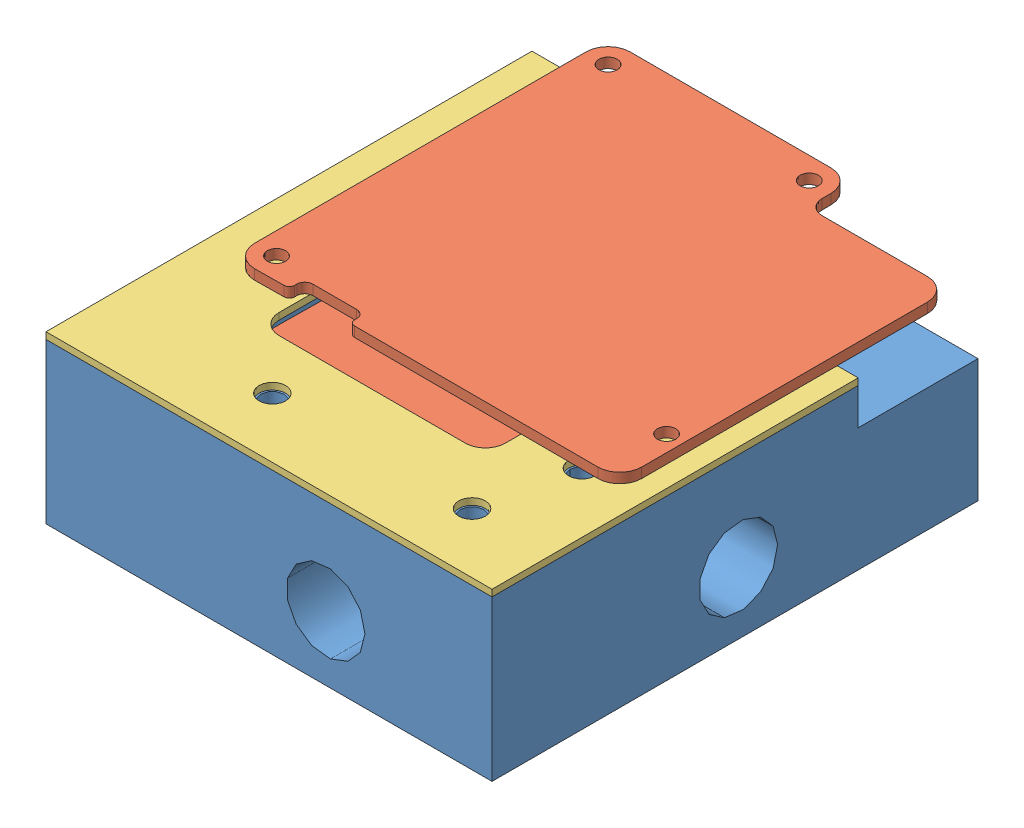
SolidWorks assembly SCK2.0Assembly, configuration Default. Lengths in mm.
Overall size (73.34 36 73).
3 component instances, 3 part files, 7 mates.
Components (placement in the parent):
- BaseSCK2.0-1: BaseSCK2.0 [Default] at origin size (67 24 73)
- SCK2.0MiCS-1: SCK2.0MiCS [Default] at (73.878 20.007 -12.5536) x (-1 0 0) z (0 0 -1) size (58.4 15.1 56.64)
- SCKClip-2: SCKClip [Default] at (52 20.5 -15) size (67 1 73)
Mates (geometry in assembly coordinates):
- Parallel1: parallel anti-aligned: plane of BaseSCK2.0-1 through (0 15 0) normal (0 1 0); plane of SCK2.0MiCS-1 through (15.1618 18.5 -23.4268) normal (0 -1 0)
- Parallel2: parallel aligned: plane of BaseSCK2.0-1 through (0 15 0) normal (-1 0 0); plane of SCK2.0MiCS-1 through (40.5073 17.4 -32.8429) normal (-1 0 0)
- Coincident1: coincident anti-aligned: plane of BaseSCK2.0-1 through (0 18.5 0) normal (0 1 0); plane of SCK2.0MiCS-1 through (15.1618 18.5 -23.4268) normal (0 -1 0)
- Concentric1: concentric aligned: circle of BaseSCK2.0-1; circle of SCK2.0MiCS-1
- Coincident2: coincident anti-aligned: plane of BaseSCK2.0-1 through (0 20.5 0) normal (0 1 0); plane of SCKClip-2 through (46 20.5 -20) normal (0 -1 0)
- Concentric3: concentric aligned: cylinder of BaseSCK2.0-1 through (58 10.5 -47.5) axis (0 1 0) radius 1.75; circle of SCKClip-2
- Concentric4: concentric aligned: circle of BaseSCK2.0-1; circle of SCKClip-2
